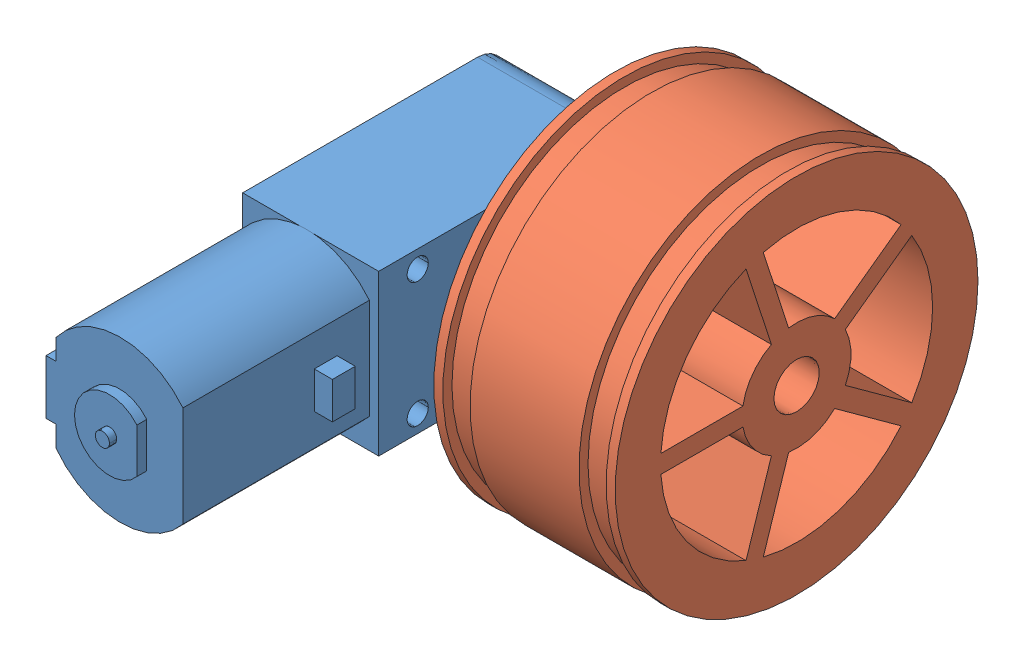
SolidWorks assembly Assem1, configuration Default. Lengths in mm.
Overall size (54.61 50.8 79.41).
2 component instances, 2 part files, 3 mates.
Components (placement in the parent):
- GearBox (1).step-1: GearBox (1).step [Default] at (5.2923 49.5182 55.9221) size (29.21 22.48 70.02)
- this wheel sld-1: this wheel sld [Default] at (47.8373 61.833 48.7796) x (0 0 1) z (0 -1 0) size (50.8 33.02 50.8)
Mates (geometry in assembly coordinates):
- Coincident1: coincident: plane of GearBox (1).step-1 through (22.4373 63.611 55.9221) normal (0 1 0); plane of this wheel sld-1 through (47.6564 63.611 48.7796) normal (0 -1 0)
- Concentric1: concentric: cylinder of GearBox (1).step-1 through (22.4373 61.833 48.7796) axis (-1 0 0) radius 2.794; cylinder of this wheel sld-1 through (47.6564 61.833 48.7796) axis (-1 0 0) radius 2.794
- Coincident3: coincident anti-aligned: plane of GearBox (1).step-1 through (14.8173 71.921 74.2736) normal (1 0 0); plane of this wheel sld-1 through (14.8173 61.833 48.7796) normal (-1 0 0)
